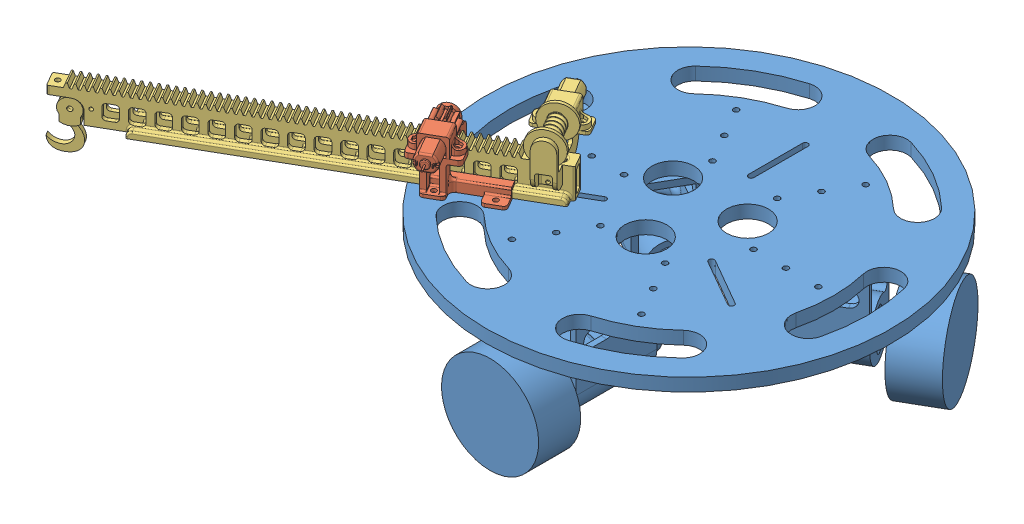
SolidWorks assembly mike_assembly_crane, configuration Default. Lengths in mm.
Overall size (796.11 403.58 521.78).
3 component instances, 3 part files, 5 mates.
Components (placement in the parent):
- honnun-robot-1: honnun-robot [Default] at (84.2788 -30.9978 208.1719) size (250 76.95 250)
- crane-extension-gear-1: crane-extension-gear [crane-extension-gear] at (-14.2507 178.5785 259.2781) x (0.5 0 0.866025) z (-0.866025 0 0.5) size (56.9 33.76 47.34)
- crane-jib-1: crane-jib [crane-jib] at (-157.5254 152.0022 353.5512) x (0.866025 0 -0.5) z (0.5 0 0.866025) size (857.13 403.58 107.64)
Mates (geometry in assembly coordinates):
- Concentric9: concentric anti-aligned: cylinder of honnun-robot-1 through (-3.5375 152.0022 277.8341) axis (0 -1 0) radius 1.6; cylinder of crane-extension-gear-1 through (-3.5375 142.4259 277.8341) axis (0 1 0) radius 1.6
- Concentric10: concentric anti-aligned: cylinder of honnun-robot-1 through (20.7113 152.0022 263.8341) axis (0 -1 0) radius 1.6; cylinder of crane-extension-gear-1 through (20.7113 142.4259 263.8341) axis (0 1 0) radius 1.6
- Coincident4: coincident anti-aligned: plane of honnun-robot-1 through (84.2788 152.0022 208.1719) normal (0 1 0); plane of crane-jib-1 through (-162.5254 152.0022 344.8909) normal (0 -1 0)
- Coincident5: coincident: point of crane-jib-1
- Parallel5: parallel aligned: line of crane-jib-1 through (39.5623 156.0022 240.9172) axis (-0.866025 0 0.5)
